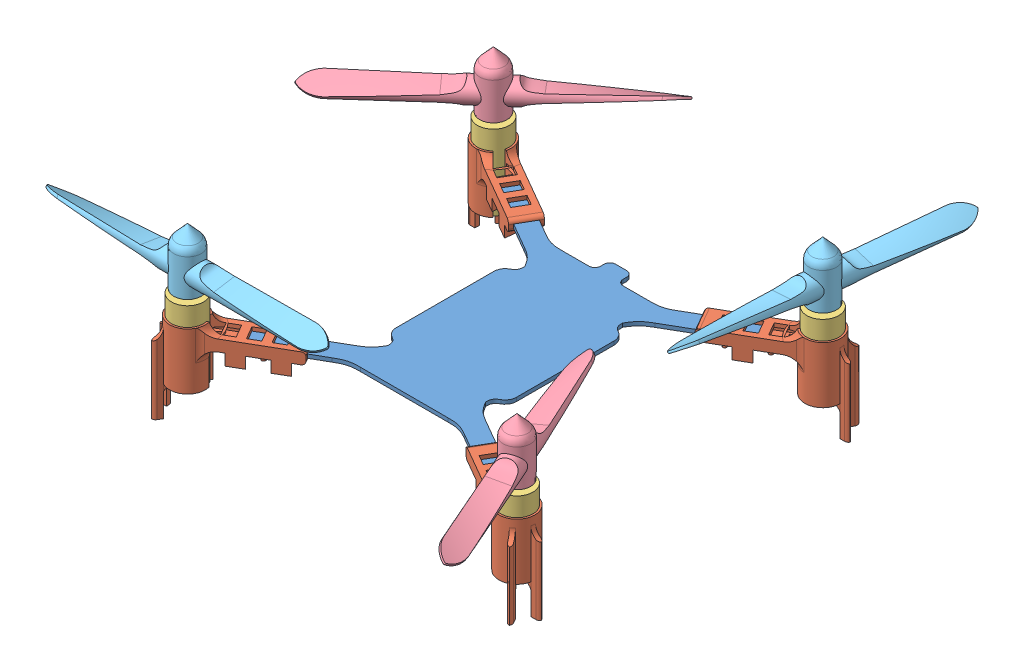
SolidWorks assembly 装配体2, configuration 默认. Lengths in mm.
Overall size (143.44 44 154.85).
13 component instances, 5 part files, 24 mates.
Components (placement in the parent):
- airplane-1: airplane [默认] at (-155.4118 -13.9876 24.712) size (69.3 1.1 73.66)
- 支架-1: 支架 [默认] at (-199.2047 -14.9876 65.3771) x (-0.866025 0 0.5) z (-0.5 0 -0.866025) size (30.17 23.28 9.5)
- 支架-2: 支架 [默认] at (-111.6188 -14.9876 -15.9531) x (0.866025 0 -0.5) z (0.5 0 0.866025) size (30.17 23.28 9.5)
- 支架-3: 支架 [默认] at (-111.6188 -14.9876 65.3771) x (0.866025 0 0.5) z (-0.5 0 0.866025) size (30.17 23.28 9.5)
- 支架-4: 支架 [默认] at (-199.2047 -14.9876 -15.9531) x (-0.866025 0 -0.5) z (0.5 0 -0.866025) size (30.17 23.28 9.5)
- 820电机-1: 820电机 [默认] at (-111.6188 -24.9876 65.3771) x (0.972646 0 -0.232292) z (0.232292 0 0.972646) size (8.5 25 8.5)
- 820电机-2: 820电机 [默认] at (-199.2047 -24.9876 65.3771) x (0.991527 0 -0.129899) z (0.129899 0 0.991527) size (8.5 25 8.5)
- 820电机-3: 820电机 [默认] at (-199.2047 -24.9876 -15.9531) x (0.999988 0 0.00499) z (-0.00499 0 0.999988) size (8.5 25 8.5)
- 820电机-4: 820电机 [默认] at (-111.6188 -24.9876 -15.9531) x (0.999635 0 0.027032) z (-0.027032 0 0.999635) size (8.5 25 8.5)
- 反浆-1: 反浆 [默认] at (-199.2047 1.0124 -15.9531) x (0.753886 0 -0.657005) z (0 -1 0) size (75.02 7.3 15)
- 反浆-4: 反浆 [默认] at (-111.6188 1.0124 65.3771) x (0.399891 0 0.916563) z (0 -1 0) size (75.02 7.3 15)
- 正浆-5: 正浆 [默认] at (-199.2047 1.0124 65.3771) x (1 0 0) z (0 -1 0) size (75.02 7.3 15)
- 正浆-6: 正浆 [默认] at (-111.6188 1.0124 -15.9531) x (0.104969 0 -0.994475) z (0 -1 0) size (75.02 7.3 15)
Mates (geometry in assembly coordinates):
- 重合7: coincident: line of assembly; line of assembly; line of airplane-1 through (-137.797 -12.9876 53.1498) axis (0.866025 0 0.5); line of 支架-3 through (-116.3666 -12.9876 65.5227) axis (-0.866025 0 -0.5)
- 重合10: coincident: line of assembly; line of assembly; line of airplane-1 through (-120.7611 -12.9876 57.212) axis (-0.866025 0 -0.5); line of 支架-3 through (-113.8666 -12.9876 61.1926) axis (-0.866025 0 -0.5)
- 重合3: coincident: line of assembly; line of assembly; line of airplane-1 through (-187.5624 -12.9876 61.5421) axis (0.866025 0 -0.5); line of 支架-1 through (-194.4569 -12.9876 65.5227) axis (0.866025 0 -0.5)
- 重合4: coincident: line of assembly; line of assembly; line of airplane-1 through (-172.7579 -12.9876 47.2213) axis (-0.866025 0 0.5); line of 支架-1 through (-196.9569 -12.9876 61.1926) axis (0.866025 0 -0.5)
- 重合5: coincident: plane of assembly; line of assembly; plane of airplane-1 through (-155.4118 -12.9876 24.712) normal (0 1 0); line of 支架-1 through (-194.4569 -12.9876 65.5227) axis (0.866025 0 -0.5)
- 重合6: coincident: line of assembly; line of assembly; line of airplane-1 through (-173.0265 -12.9876 -3.7258) axis (-0.866025 0 -0.5); line of 支架-4 through (-194.4569 -12.9876 -16.0987) axis (0.866025 0 0.5)
- 重合7: coincident: line of assembly; line of assembly; line of airplane-1 through (-190.0624 -12.9876 -7.788) axis (0.866025 0 0.5); line of 支架-4 through (-196.9569 -12.9876 -11.7686) axis (0.866025 0 0.5)
- 重合8: coincident: line of assembly; line of assembly; line of airplane-1 through (-123.2611 -12.9876 -12.1181) axis (-0.866025 0 0.5); line of 支架-2 through (-116.3666 -12.9876 -16.0987) axis (-0.866025 0 0.5)
- 平行1: parallel: line of assembly; line of assembly; line of airplane-1 through (-138.0656 -13.9876 2.2027) axis (0.866025 0 -0.5); line of 支架-2 through (-113.8666 -12.9876 -11.7686) axis (-0.866025 0 0.5)
- 重合10: coincident: line of assembly; line of assembly; line of airplane-1 through (-138.0656 -12.9876 2.2027) axis (0.866025 0 -0.5); line of 支架-2 through (-113.8666 -12.9876 -11.7686) axis (-0.866025 0 0.5)
- 重合12: coincident: circle of assembly; circle of assembly; circle of 支架-3; circle of 820电机-1
- 重合13: coincident: circle of assembly; circle of assembly; circle of 支架-1; circle of 820电机-2
- 重合14: coincident: circle of assembly; circle of assembly; circle of 支架-4; circle of 820电机-3
- 重合15: coincident: circle of assembly; circle of assembly; circle of 支架-2; circle of 820电机-4
- 同心2: concentric: circle of 820电机-3; circle of ?
- 同心4: concentric: circle of 820电机-1; circle of ?
- 重合21: coincident: circle of 820电机-2; circle of ?
- 重合22: coincident: circle of 820电机-4; circle of ?
- 重合24: coincident: circle of ?; circle of 820电机-1
- 重合25: coincident: circle of 820电机-3; circle of ?
- 重合26: coincident: line of assembly; line of assembly; line of airplane-1 through (-120.7611 -12.9876 -7.788) axis (-0.5 0 -0.866025); line of 支架-2 through (-123.0111 -12.9876 -11.6851) axis (0.5 0 0.866025)
- 重合27: coincident: line of assembly; line of assembly; line of airplane-1 through (-123.2611 -12.9876 61.5421) axis (0.5 0 -0.866025); line of 支架-3 through (-121.0111 -12.9876 57.645) axis (-0.5 0 0.866025)
- 重合29: coincident: line of assembly; line of assembly; line of airplane-1 through (-190.0624 -12.9876 57.212) axis (0.5 0 0.866025); line of 支架-1 through (-187.8124 -12.9876 61.1091) axis (-0.5 0 -0.866025)
- 重合30: coincident: line of assembly; line of assembly; line of airplane-1 through (-187.5624 -12.9876 -12.1181) axis (-0.5 0 0.866025); line of 支架-4 through (-189.8124 -12.9876 -8.221) axis (0.5 0 -0.866025)
